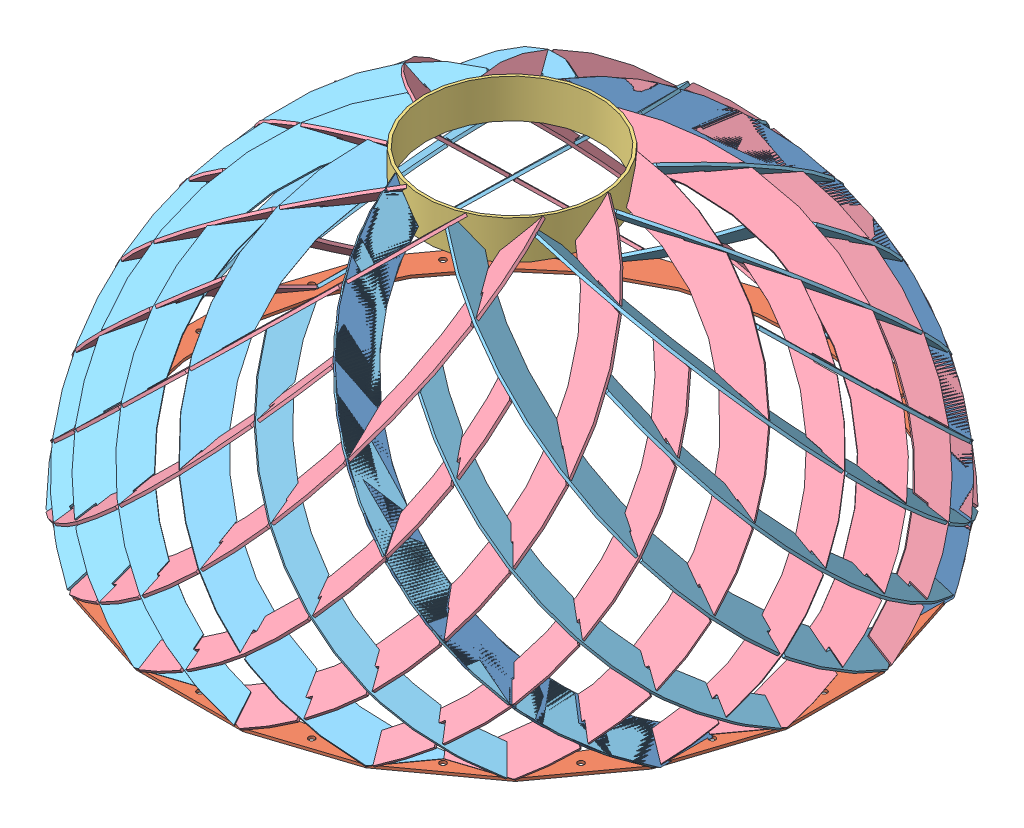
SolidWorks assembly frame1, configuration Default. Lengths in mm.
Overall size (896.02 367.2 894.17).
44 component instances, 6 part files, 15 mates.
Components (placement in the parent):
- sphere_outline-1: sphere_outline [Default] at origin size (762 758.6 762) (hidden)
- rib-1: rib [Default] x (-1 0 0) z (0 1 0) size (381.83 596.96 365.18)
- waist-1: waist [Default] x (-1 0 0) z (0 1 0) size (743.4 741.73 3.17)
- axle_frame-1: axle_frame [Default] at (0 -6.0987 0) x (-1 0 0) z (0 1 0) size (203.2 203.2 44.45)
- inside_rib-1: inside_rib [Default] x (1 0 0) z (0 1 0) size (379.15 205.09 365.17)
- outside_rib-1: outside_rib [Default] x (1 0 0) z (0 1 0) size (373.79 201.22 360.01)
- outside_rib-2: outside_rib [Default] x (0.809017 0 -0.587785) z (0 1 0) size (373.79 201.22 360.01)
- outside_rib-3: outside_rib [Default] x (0.309017 0 -0.951057) z (0 1 0) size (373.79 201.22 360.01)
- outside_rib-4: outside_rib [Default] x (-0.309017 0 -0.951057) z (0 1 0) size (373.79 201.22 360.01)
- outside_rib-5: outside_rib [Default] x (-0.809017 0 -0.587785) z (0 1 0) size (373.79 201.22 360.01)
- outside_rib-6: outside_rib [Default] x (-1 0 0) z (0 1 0) size (373.79 201.22 360.01)
- outside_rib-7: outside_rib [Default] x (-0.809017 0 0.587785) z (0 1 0) size (373.79 201.22 360.01)
- outside_rib-8: outside_rib [Default] x (-0.309017 0 0.951057) z (0 1 0) size (373.79 201.22 360.01)
- outside_rib-9: outside_rib [Default] x (0.309017 0 0.951057) z (0 1 0) size (373.79 201.22 360.01)
- inside_rib-2: inside_rib [Default] x (0.809017 0 -0.587785) z (0 1 0) size (379.15 205.09 365.17)
- inside_rib-3: inside_rib [Default] x (0.309017 0 -0.951057) z (0 1 0) size (379.15 205.09 365.17)
- inside_rib-4: inside_rib [Default] x (-0.309017 0 -0.951057) z (0 1 0) size (379.15 205.09 365.17)
- inside_rib-5: inside_rib [Default] x (-0.809017 0 -0.587785) z (0 1 0) size (379.15 205.09 365.17)
- inside_rib-6: inside_rib [Default] x (-1 0 0) z (0 1 0) size (379.15 205.09 365.17)
- inside_rib-7: inside_rib [Default] x (-0.809017 0 0.587785) z (0 1 0) size (379.15 205.09 365.17)
- inside_rib-8: inside_rib [Default] x (-0.309017 0 0.951057) z (0 1 0) size (379.15 205.09 365.17)
- inside_rib-9: inside_rib [Default] x (0.309017 0 0.951057) z (0 1 0) size (379.15 205.09 365.17)
- outside_rib-10: outside_rib [Default] x (0.809017 0 0.587785) z (0 1 0) size (373.79 201.22 360.01)
- inside_rib-10: inside_rib [Default] x (0.809017 0 0.587785) z (0 1 0) size (379.15 205.09 365.17)
- inside_rib-21: inside_rib [short] x (0.951057 0 -0.309017) z (0 1 0) size (304.88 133.31 293.67)
- inside_rib-22: inside_rib [short] x (0.587785 0 -0.809017) z (0 1 0) size (304.88 133.31 293.67)
- inside_rib-23: inside_rib [short] x (0 0 -1) z (0 1 0) size (304.88 133.31 293.67)
- inside_rib-24: inside_rib [short] x (-0.587785 0 -0.809017) z (0 1 0) size (304.88 133.31 293.67)
- inside_rib-25: inside_rib [short] x (-0.951057 0 -0.309017) z (0 1 0) size (304.88 133.31 293.67)
- inside_rib-26: inside_rib [short] x (-0.951057 0 0.309017) z (0 1 0) size (304.88 133.31 293.67)
- inside_rib-27: inside_rib [short] x (-0.587785 0 0.809017) z (0 1 0) size (304.88 133.31 293.67)
- inside_rib-28: inside_rib [short] x (0 0 1) z (0 1 0) size (304.88 133.31 293.67)
- inside_rib-29: inside_rib [short] x (0.587785 0 0.809017) z (0 1 0) size (304.88 133.31 293.67)
- inside_rib-30: inside_rib [short] x (0.951057 0 0.309017) z (0 1 0) size (304.88 133.31 293.67)
- outside_rib-21: outside_rib [short] x (0.951057 0 -0.309017) z (0 1 0) size (304.88 133.31 293.67)
- outside_rib-22: outside_rib [short] x (0.587785 0 -0.809017) z (0 1 0) size (304.88 133.31 293.67)
- outside_rib-23: outside_rib [short] x (0 0 -1) z (0 1 0) size (304.88 133.31 293.67)
- outside_rib-24: outside_rib [short] x (-0.587785 0 -0.809017) z (0 1 0) size (304.88 133.31 293.67)
- outside_rib-25: outside_rib [short] x (-0.951057 0 -0.309017) z (0 1 0) size (304.88 133.31 293.67)
- outside_rib-26: outside_rib [short] x (-0.951057 0 0.309017) z (0 1 0) size (304.88 133.31 293.67)
- outside_rib-27: outside_rib [short] x (-0.587785 0 0.809017) z (0 1 0) size (304.88 133.31 293.67)
- outside_rib-28: outside_rib [short] x (0 0 1) z (0 1 0) size (304.88 133.31 293.67)
- outside_rib-29: outside_rib [short] x (0.587785 0 0.809017) z (0 1 0) size (304.88 133.31 293.67)
- outside_rib-30: outside_rib [short] x (0.951057 0 0.309017) z (0 1 0) size (304.88 133.31 293.67)
Mates (geometry in assembly coordinates):
- InPlace1: in place: plane of ?
- Coincident1: coincident aligned: plane of ?; plane of assembly
- Coincident2: coincident aligned: plane of ?; moOrthogonalPlaneRef_w of assembly
- Coincident3: coincident anti-aligned: plane of ?; moOrthogonalPlaneRef_w of assembly
- InPlace2: in place: unknown of ?
- Coincident4: coincident aligned: plane of ?; plane of assembly
- Coincident5: coincident aligned: plane of ?; moOrthogonalPlaneRef_w of assembly
- Coincident6: coincident anti-aligned: plane of ?; moOrthogonalPlaneRef_w of assembly
- Coincident3: coincident aligned: plane of ? through (0 0 0) normal (0 1 0); plane of ? through (0 0 0) normal (0 1 0)
- Coincident4: coincident anti-aligned: plane of ? through (0 0 0) normal (0 0 1); plane of ? through (0 0 0) normal (0 0 -1)
- Coincident5: coincident anti-aligned: plane of ? through (0 0 0) normal (-1 0 0); plane of ? through (0 0 0) normal (1 0 0)
- Coincident6: coincident aligned: plane of ? through (0 0 0) normal (0 1 0); plane of ? through (0 0 0) normal (0 1 0)
- Coincident7: coincident anti-aligned: plane of ? through (0 0 0) normal (0 0 1); plane of ? through (0 0 0) normal (0 0 -1)
- Coincident8: coincident anti-aligned: plane of ? through (0 0 0) normal (-1 0 0); plane of ? through (0 0 0) normal (1 0 0)
- Coincident11: coincident: circle of axle_frame-1; point of ?
